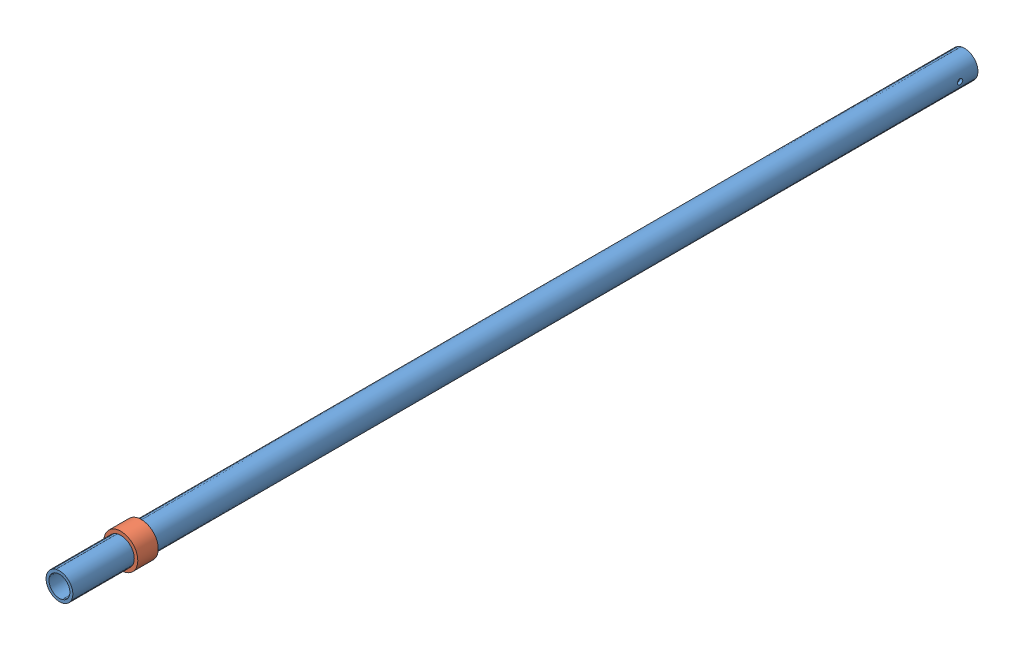
SolidWorks assembly GE-18039, configuration Default. Lengths in mm.
Overall size (42.16 42.16 1123.95).
2 component instances, 2 part files, 0 mates.
Components (placement in the parent):
- GE-18039-01-1: GE-18039-01 [Default] at (-1200.15 -561.975 298.45) x (0 -1 0) z (0 0 1) size (33.4 33.4 1123.95)
- GE-18039-02-1: GE-18039-02 [Default] at (-1286.9983 36.6281 235.0514) x (0 -1 0) z (0 0 1) size (42.16 42.16 25.4)
